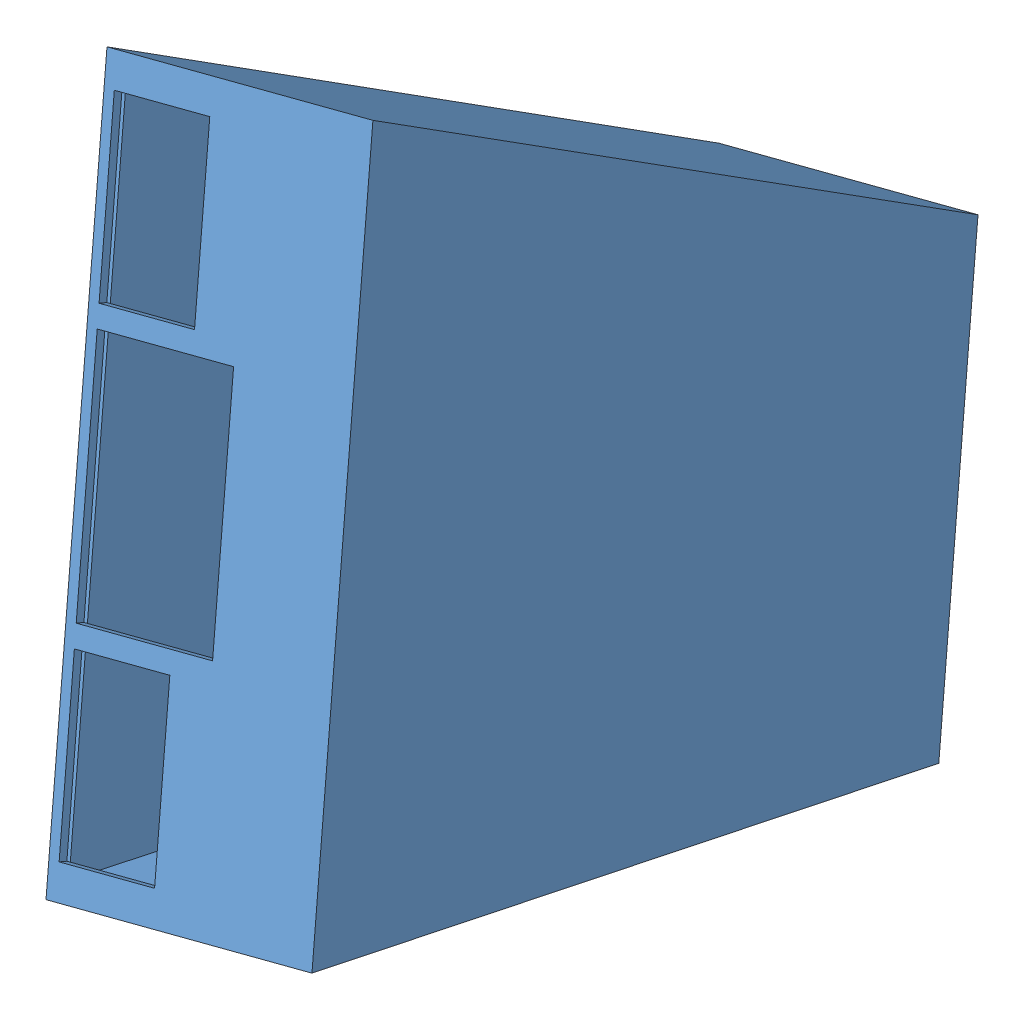
SolidWorks assembly full chassis assembly, configuration Default. Lengths in mm.
Overall size (678.3 1127.44 1052.06).
12 component instances, 8 part files, 12 mates.
Components (placement in the parent):
- chassis-1: chassis [Default] at (91.126 491.4912 430.0303) x (0.120566 -0.324701 -0.938101) z (0.961756 0.272331 0.029346) size (800 840.7 390)
- DC Motor-1: DC Motor [Default] at (149.9378 231.7086 504.4629) x (-0.268112 0.957911 -0.102582) z (-0.961756 -0.272331 -0.029346) size (36.8 36.8 90.1)
- DC Motor-2: DC Motor [Default] at (14.4446 730.6996 314.3354) x (-0.208522 0.797425 -0.566243) z (-0.961756 -0.272331 -0.029346) size (36.8 36.8 90.1)
- TFmini-S Micro Lidar-1: TFmini-S Micro Lidar [Default] at (-1.0966 641.1351 -55.51) x (-0.961756 -0.272331 -0.029346) z (-0.163826 0.486061 0.858432) size (42 16.01 21.5)
- TFmini-S Micro Lidar-3: TFmini-S Micro Lidar [Default] at (159.1575 50.9554 169.3625) x (0.961756 0.272331 0.029346) z (-0.073176 0.152218 0.985634) size (42 16.01 21.5)
- final_assembly.STEP-1: final_assembly.STEP [Default] at (48.4542 215.1294 89.5047) x (0.960984 0.274355 0.035208) z (-0.126575 0.322993 0.937899) size (38 52.2 24.29)
  - Raspberry Pi HQ Camera..STEP-1: Raspberry Pi HQ Camera..STEP [Default] at (14.8833 32.0865 32.8515) size (38 52.2 18.71)
  - fillister head screw_ai_CR-FIMS 0.086-64x0.188x0.188-N.STEP-1: fillister head screw_ai_CR-FIMS 0.086-64x0.188x0.188-N.STEP [Default] at (26.415 9.4009 40.6012) x (-0.615365 0.788242 0) z (-0.008913 -0.006959 0.999936) size (6.86 3.56 3.56)
  - fillister head screw_ai_CR-FIMS 0.086-64x0.188x0.188-N.STEP-2: fillister head screw_ai_CR-FIMS 0.086-64x0.188x0.188-N.STEP [Default] at (3.4104 9.4761 40.6012) x (0.615365 0.788242 0) z (0 0 1) size (6.86 3.56 3.56)
  - fillister head screw_ai_CR-FIMS 0.06-80x0.3125x0.3125-N.STEP-1: fillister head screw_ai_CR-FIMS 0.06-80x0.3125x0.3125-N.STEP [Default] at (20.5603 51.8367 41.9415) x (-1 0 0) z (0 -0.621425 -0.783474) size (9.31 2.44 2.44)
  - Camera Connector from RPi4ModelB.STEP-1: Camera Connector from RPi4ModelB.STEP [Default] at (14.7087 15.5365 32.6515) x (-1 0 0) z (0 -1 0) size (22.4 5.68 5.07)
- Neopixel Ring 35 5volt v1.step-1: Neopixel Ring 35 5volt v1.step [Default] at (21.6608 388.2981 75.6303) x (0.991733 0.021096 0.126575) z (-0.126575 0.322993 0.937899) size (112 112 3)
Mates (geometry in assembly coordinates):
- Tangent5: tangent anti-aligned: plane of chassis-1 through (92.3316 488.2442 420.6493) normal (0.120566 -0.324701 -0.938101); cylinder of DC Motor-1 through (192.6474 243.0557 498.794) axis (-0.961756 -0.272331 -0.029346) radius 18.4
- Distance7: distance = 105 mm: cylinder of DC Motor-1 through (192.6474 243.0557 498.794) axis (-0.961756 -0.272331 -0.029346) radius 18.4; line of chassis-1 through (-34.0191 286.308 474.3058) axis (0.961756 0.272331 0.029346)
- Distance8: distance = 28 mm: line of DC Motor-1 through (150.5671 229.7185 502.308) axis (-0.268112 0.957911 -0.102582); line of chassis-1 through (95.7579 323.0557 478.2657) axis (0.245946 -0.905762 0.345117)
- Parallel7: parallel anti-aligned: line of chassis-1 through (289.5911 504.4673 -401.7408) axis (-0.961756 -0.272331 -0.029346); line of TFmini-S Micro Lidar-1 through (-14.1029 633.4589 -62.3826) axis (0.961756 0.272331 0.029346)
- Coincident6: coincident anti-aligned: plane of chassis-1 through (289.5911 504.4673 -401.7408) normal (0.219514 -0.83041 0.512087); plane of TFmini-S Micro Lidar-1 through (-1.0966 641.1351 -55.51) normal (-0.219514 0.83041 -0.512087)
- Distance9: distance = 400 mm: line of chassis-1 through (162.6617 896.4917 288.3832) axis (-0.961756 -0.272331 -0.029346); line of TFmini-S Micro Lidar-1 through (-14.1029 633.4589 -62.3826) axis (0.961756 0.272331 0.029346)
- Coincident12: coincident anti-aligned: circle of Wheel (Version 3)-1; circle of DC Motor-1
- Parallel14: parallel anti-aligned: plane of chassis-1 through (91.8786 446.7345 48.9751) normal (-0.126575 0.322993 0.937899); plane of final_assembly.STEP-1/Raspberry Pi HQ Camera..STEP-1 through (38.7481 238.3223 113.5776) normal (0.126575 -0.322993 -0.937899)
- Coincident14: coincident anti-aligned: plane of chassis-1 through (89.392 455.5767 47.2513) normal (-0.126575 0.322993 0.937899); plane of final_assembly.STEP-1/Raspberry Pi HQ Camera..STEP-1 through (38.5514 238.8242 115.035) normal (0.126575 -0.322993 -0.937899)
- Parallel15: parallel anti-aligned: line of chassis-1 through (89.392 455.5767 47.2513) axis (0.245946 -0.905762 0.345117); line of final_assembly.STEP-1/Raspberry Pi HQ Camera..STEP-1 through (72.8735 249.1258 117.612) axis (-0.245946 0.905762 -0.345117)
- Coincident22: coincident anti-aligned: line of chassis-1 through (141.0678 265.582 117.9986) axis (-0.960984 -0.274355 -0.035208); line of final_assembly.STEP-1/Raspberry Pi HQ Camera..STEP-1 through (39.24 236.5108 114.2678) axis (0.960984 0.274355 0.035208)
- Lock3: lock: unknown of chassis-1; unknown of Neopixel Ring 35 5volt v1.step-1
